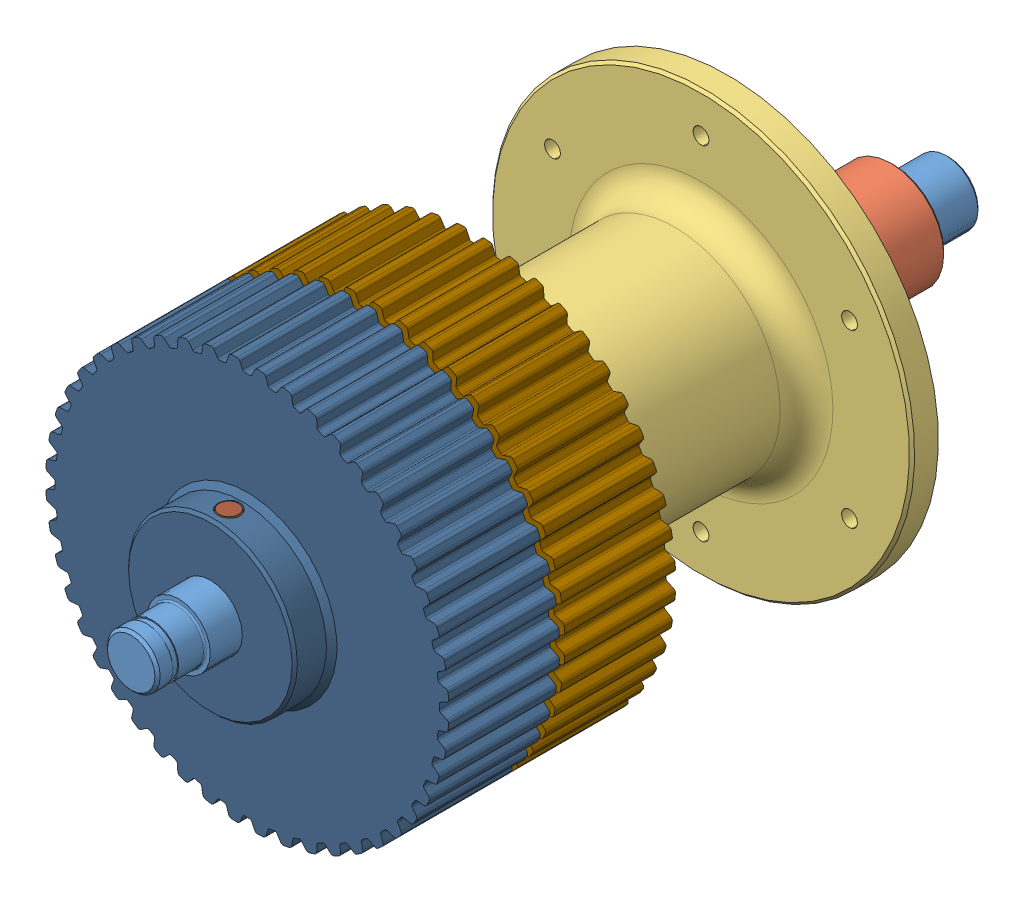
SolidWorks assembly Coaxial Shaft Assembly, configuration Default. Lengths in mm.
Overall size (109.28 109.28 155).
87 component instances, 12 part files, 29 mates.
Components (placement in the parent):
- Inner Shaft-1: Inner Shaft [Default] at (94.2981 61.5422 207.3778) x (0 0 -1) z (1 0 0) size (155 12 12)
- Outer Shaft-1: Outer Shaft [Default] at (94.2981 61.5422 163.3778) x (0 0 -1) z (-1 0 0) size (100.5 20 20)
- Flange-1: Flange [Default] at (94.2981 61.5422 94.3778) x (-0.866025 0.5 0) z (0 0 1) size (80 80 40)
- SKF - 61804 - 18,SI,NC,18_68-5: SKF - 61804 - 18,SI,NC,18_68 [SKF - 61804 - 18,SI,NC,18_68] at (94.2981 61.5422 97.8778) x (0 0 1) z (-0.071685 -0.997427 0) size (7 32 32)
- SKF - 61804 - 18,SI,NC,18_68-6: SKF - 61804 - 18,SI,NC,18_68 [SKF - 61804 - 18,SI,NC,18_68] at (94.2981 61.5422 130.8778) x (0 0 1) z (-1 0 0) size (7 32 32)
- Circlip DIN 471 - 20 x 1.2-3: Circlip DIN 471 - 20 x 1.2 [Circlip DIN 471 - 20 x 1.2] at (94.2981 61.5422 93.0778) x (-1 0 0) z (0 0 -1) size (22.81 25.6 1.2)
- HK_1210-1: HK_1210 [Default] at (94.2981 61.5422 163.3778) x (0 0 -1) z (1 0 0) size (10 16 16)
  - _HK_1210_PART1_2-1: _HK_1210_PART1_2 [Default] at origin size (10 16 16)
  - _HK_1210_PART2_4-1: _HK_1210_PART2_4 [Default] at origin size (6.3 1.5 1.5)
  - _HK_1210_PART2_4-2: _HK_1210_PART2_4 [Default] x (1 0 0) z (0 0.34202 0.939693) size (6.3 1.5 1.5)
  - _HK_1210_PART2_4-3: _HK_1210_PART2_4 [Default] x (1 0 0) z (0 0.642788 0.766044) size (6.3 1.5 1.5)
  - _HK_1210_PART2_4-4: _HK_1210_PART2_4 [Default] x (1 0 0) z (0 0.866025 0.5) size (6.3 1.5 1.5)
  - _HK_1210_PART2_4-5: _HK_1210_PART2_4 [Default] x (1 0 0) z (0 0.984808 0.173648) size (6.3 1.5 1.5)
  - _HK_1210_PART2_4-6: _HK_1210_PART2_4 [Default] x (1 0 0) z (0 0.984808 -0.173648) size (6.3 1.5 1.5)
  - _HK_1210_PART2_4-7: _HK_1210_PART2_4 [Default] x (1 0 0) z (0 0.866025 -0.5) size (6.3 1.5 1.5)
  - _HK_1210_PART2_4-8: _HK_1210_PART2_4 [Default] x (1 0 0) z (0 0.642788 -0.766044) size (6.3 1.5 1.5)
  - _HK_1210_PART2_4-9: _HK_1210_PART2_4 [Default] x (1 0 0) z (0 0.34202 -0.939693) size (6.3 1.5 1.5)
  - _HK_1210_PART2_4-10: _HK_1210_PART2_4 [Default] x (1 0 0) z (0 0 -1) size (6.3 1.5 1.5)
  - _HK_1210_PART2_4-11: _HK_1210_PART2_4 [Default] x (1 0 0) z (0 -0.34202 -0.939693) size (6.3 1.5 1.5)
  - _HK_1210_PART2_4-12: _HK_1210_PART2_4 [Default] x (1 0 0) z (0 -0.642788 -0.766044) size (6.3 1.5 1.5)
  - _HK_1210_PART2_4-13: _HK_1210_PART2_4 [Default] x (1 0 0) z (0 -0.866025 -0.5) size (6.3 1.5 1.5)
  - _HK_1210_PART2_4-14: _HK_1210_PART2_4 [Default] x (1 0 0) z (0 -0.984808 -0.173648) size (6.3 1.5 1.5)
  - _HK_1210_PART2_4-15: _HK_1210_PART2_4 [Default] x (1 0 0) z (0 -0.984808 0.173648) size (6.3 1.5 1.5)
  - _HK_1210_PART2_4-16: _HK_1210_PART2_4 [Default] x (1 0 0) z (0 -0.866025 0.5) size (6.3 1.5 1.5)
  - _HK_1210_PART2_4-17: _HK_1210_PART2_4 [Default] x (1 0 0) z (0 -0.642788 0.766044) size (6.3 1.5 1.5)
  - _HK_1210_PART2_4-18: _HK_1210_PART2_4 [Default] x (1 0 0) z (0 -0.34202 0.939693) size (6.3 1.5 1.5)
  - _HK_1210_PART3_23-1: _HK_1210_PART3_23 [Default] at origin size (6.3 1.5 1.5)
  - _HK_1210_PART3_23-2: _HK_1210_PART3_23 [Default] x (1 0 0) z (0 0.34202 0.939693) size (6.3 1.5 1.5)
  - _HK_1210_PART3_23-3: _HK_1210_PART3_23 [Default] x (1 0 0) z (0 0.642788 0.766044) size (6.3 1.5 1.5)
  - _HK_1210_PART3_23-4: _HK_1210_PART3_23 [Default] x (1 0 0) z (0 0.866025 0.5) size (6.3 1.5 1.5)
  - _HK_1210_PART3_23-5: _HK_1210_PART3_23 [Default] x (1 0 0) z (0 0.984808 0.173648) size (6.3 1.5 1.5)
  - _HK_1210_PART3_23-6: _HK_1210_PART3_23 [Default] x (1 0 0) z (0 0.984808 -0.173648) size (6.3 1.5 1.5)
  - _HK_1210_PART3_23-7: _HK_1210_PART3_23 [Default] x (1 0 0) z (0 0.866025 -0.5) size (6.3 1.5 1.5)
  - _HK_1210_PART3_23-8: _HK_1210_PART3_23 [Default] x (1 0 0) z (0 0.642788 -0.766044) size (6.3 1.5 1.5)
  - _HK_1210_PART3_23-9: _HK_1210_PART3_23 [Default] x (1 0 0) z (0 0.34202 -0.939693) size (6.3 1.5 1.5)
  - _HK_1210_PART3_23-10: _HK_1210_PART3_23 [Default] x (1 0 0) z (0 0 -1) size (6.3 1.5 1.5)
  - _HK_1210_PART3_23-11: _HK_1210_PART3_23 [Default] x (1 0 0) z (0 -0.34202 -0.939693) size (6.3 1.5 1.5)
  - _HK_1210_PART3_23-12: _HK_1210_PART3_23 [Default] x (1 0 0) z (0 -0.642788 -0.766044) size (6.3 1.5 1.5)
  - _HK_1210_PART3_23-13: _HK_1210_PART3_23 [Default] x (1 0 0) z (0 -0.866025 -0.5) size (6.3 1.5 1.5)
  - _HK_1210_PART3_23-14: _HK_1210_PART3_23 [Default] x (1 0 0) z (0 -0.984808 -0.173648) size (6.3 1.5 1.5)
  - _HK_1210_PART3_23-15: _HK_1210_PART3_23 [Default] x (1 0 0) z (0 -0.984808 0.173648) size (6.3 1.5 1.5)
  - _HK_1210_PART3_23-16: _HK_1210_PART3_23 [Default] x (1 0 0) z (0 -0.866025 0.5) size (6.3 1.5 1.5)
  - _HK_1210_PART3_23-17: _HK_1210_PART3_23 [Default] x (1 0 0) z (0 -0.642788 0.766044) size (6.3 1.5 1.5)
  - _HK_1210_PART3_23-18: _HK_1210_PART3_23 [Default] x (1 0 0) z (0 -0.34202 0.939693) size (6.3 1.5 1.5)
- HK_1210-2: HK_1210 [Default] at (94.2981 61.5422 72.8778) x (0 0 -1) z (1 0 0) size (10 16 16)
  - _HK_1210_PART1_2-1: _HK_1210_PART1_2 [Default] at origin size (10 16 16)
  - _HK_1210_PART2_4-1: _HK_1210_PART2_4 [Default] at origin size (6.3 1.5 1.5)
  - _HK_1210_PART2_4-2: _HK_1210_PART2_4 [Default] x (1 0 0) z (0 0.34202 0.939693) size (6.3 1.5 1.5)
  - _HK_1210_PART2_4-3: _HK_1210_PART2_4 [Default] x (1 0 0) z (0 0.642788 0.766044) size (6.3 1.5 1.5)
  - _HK_1210_PART2_4-4: _HK_1210_PART2_4 [Default] x (1 0 0) z (0 0.866025 0.5) size (6.3 1.5 1.5)
  - _HK_1210_PART2_4-5: _HK_1210_PART2_4 [Default] x (1 0 0) z (0 0.984808 0.173648) size (6.3 1.5 1.5)
  - _HK_1210_PART2_4-6: _HK_1210_PART2_4 [Default] x (1 0 0) z (0 0.984808 -0.173648) size (6.3 1.5 1.5)
  - _HK_1210_PART2_4-7: _HK_1210_PART2_4 [Default] x (1 0 0) z (0 0.866025 -0.5) size (6.3 1.5 1.5)
  - _HK_1210_PART2_4-8: _HK_1210_PART2_4 [Default] x (1 0 0) z (0 0.642788 -0.766044) size (6.3 1.5 1.5)
  - _HK_1210_PART2_4-9: _HK_1210_PART2_4 [Default] x (1 0 0) z (0 0.34202 -0.939693) size (6.3 1.5 1.5)
  - _HK_1210_PART2_4-10: _HK_1210_PART2_4 [Default] x (1 0 0) z (0 0 -1) size (6.3 1.5 1.5)
  - _HK_1210_PART2_4-11: _HK_1210_PART2_4 [Default] x (1 0 0) z (0 -0.34202 -0.939693) size (6.3 1.5 1.5)
  - _HK_1210_PART2_4-12: _HK_1210_PART2_4 [Default] x (1 0 0) z (0 -0.642788 -0.766044) size (6.3 1.5 1.5)
  - _HK_1210_PART2_4-13: _HK_1210_PART2_4 [Default] x (1 0 0) z (0 -0.866025 -0.5) size (6.3 1.5 1.5)
  - _HK_1210_PART2_4-14: _HK_1210_PART2_4 [Default] x (1 0 0) z (0 -0.984808 -0.173648) size (6.3 1.5 1.5)
  - _HK_1210_PART2_4-15: _HK_1210_PART2_4 [Default] x (1 0 0) z (0 -0.984808 0.173648) size (6.3 1.5 1.5)
  - _HK_1210_PART2_4-16: _HK_1210_PART2_4 [Default] x (1 0 0) z (0 -0.866025 0.5) size (6.3 1.5 1.5)
  - _HK_1210_PART2_4-17: _HK_1210_PART2_4 [Default] x (1 0 0) z (0 -0.642788 0.766044) size (6.3 1.5 1.5)
  - _HK_1210_PART2_4-18: _HK_1210_PART2_4 [Default] x (1 0 0) z (0 -0.34202 0.939693) size (6.3 1.5 1.5)
  - _HK_1210_PART3_23-1: _HK_1210_PART3_23 [Default] at origin size (6.3 1.5 1.5)
  - _HK_1210_PART3_23-2: _HK_1210_PART3_23 [Default] x (1 0 0) z (0 0.34202 0.939693) size (6.3 1.5 1.5)
  - _HK_1210_PART3_23-3: _HK_1210_PART3_23 [Default] x (1 0 0) z (0 0.642788 0.766044) size (6.3 1.5 1.5)
  - _HK_1210_PART3_23-4: _HK_1210_PART3_23 [Default] x (1 0 0) z (0 0.866025 0.5) size (6.3 1.5 1.5)
  - _HK_1210_PART3_23-5: _HK_1210_PART3_23 [Default] x (1 0 0) z (0 0.984808 0.173648) size (6.3 1.5 1.5)
  - _HK_1210_PART3_23-6: _HK_1210_PART3_23 [Default] x (1 0 0) z (0 0.984808 -0.173648) size (6.3 1.5 1.5)
  - _HK_1210_PART3_23-7: _HK_1210_PART3_23 [Default] x (1 0 0) z (0 0.866025 -0.5) size (6.3 1.5 1.5)
  - _HK_1210_PART3_23-8: _HK_1210_PART3_23 [Default] x (1 0 0) z (0 0.642788 -0.766044) size (6.3 1.5 1.5)
  - _HK_1210_PART3_23-9: _HK_1210_PART3_23 [Default] x (1 0 0) z (0 0.34202 -0.939693) size (6.3 1.5 1.5)
  - _HK_1210_PART3_23-10: _HK_1210_PART3_23 [Default] x (1 0 0) z (0 0 -1) size (6.3 1.5 1.5)
  - _HK_1210_PART3_23-11: _HK_1210_PART3_23 [Default] x (1 0 0) z (0 -0.34202 -0.939693) size (6.3 1.5 1.5)
  - _HK_1210_PART3_23-12: _HK_1210_PART3_23 [Default] x (1 0 0) z (0 -0.642788 -0.766044) size (6.3 1.5 1.5)
  - _HK_1210_PART3_23-13: _HK_1210_PART3_23 [Default] x (1 0 0) z (0 -0.866025 -0.5) size (6.3 1.5 1.5)
  - _HK_1210_PART3_23-14: _HK_1210_PART3_23 [Default] x (1 0 0) z (0 -0.984808 -0.173648) size (6.3 1.5 1.5)
  - _HK_1210_PART3_23-15: _HK_1210_PART3_23 [Default] x (1 0 0) z (0 -0.984808 0.173648) size (6.3 1.5 1.5)
  - _HK_1210_PART3_23-16: _HK_1210_PART3_23 [Default] x (1 0 0) z (0 -0.866025 0.5) size (6.3 1.5 1.5)
  - _HK_1210_PART3_23-17: _HK_1210_PART3_23 [Default] x (1 0 0) z (0 -0.642788 0.766044) size (6.3 1.5 1.5)
  - _HK_1210_PART3_23-18: _HK_1210_PART3_23 [Default] x (1 0 0) z (0 -0.34202 0.939693) size (6.3 1.5 1.5)
- Outer Timing Belt Gear-1: Outer Timing Belt Gear [Default] at (94.2981 61.5422 163.3778) x (1 0 0) z (0 0 -1) size (76.29 76.29 29)
- Inner Timing Belt Gear-1: Inner Timing Belt Gear [Default] at (94.2981 61.5422 164.3778) size (76.29 76.29 28)
- ISO 8734 - 4 x 32 - A - St-3: ISO 8734 - 4 x 32 - A - St [ISO 8734 - 4 x 32 - A - St] at (94.2981 45.5422 188.8778) x (0 1 0) z (0.480016 0 0.87726) size (32 4 4)
- ISO 4762 M3 x 12 - 12C-3: ISO 4762 M3 x 12 - 12C [ISO 4762 M3 x 12 - 12C] at (94.2981 39.5422 138.8778) x (0 1 0) z (0.922632 0 -0.385681) size (15 5.5 5.5)
- ISO 4762 M3 x 12 - 12C-4: ISO 4762 M3 x 12 - 12C [ISO 4762 M3 x 12 - 12C] at (94.2981 83.5422 138.8778) x (0 -1 0) z (0.974179 0 0.225776) size (15 5.5 5.5)
Mates (geometry in assembly coordinates):
- Concentric22: concentric: cylinder of Inner Shaft-1 through (94.2981 61.5422 52.3778) axis (0 0 1) radius 6; cylinder of Outer Shaft-1 through (94.2981 61.5422 62.8778) axis (0 0 1) radius 7
- Concentric23: concentric: cylinder of Outer Shaft-1 through (94.2981 61.5422 62.8778) axis (0 0 1) radius 10; cylinder of Flange-1 through (94.2981 61.5422 150.679) axis (0 0 1) radius 14.5
- Concentric466: concentric: cylinder of Outer Shaft-1 through (94.2981 61.5422 62.8778) axis (0 0 1) radius 10; cylinder of SKF - 61804 - 18,SI,NC,18_68-5 through (94.2981 61.5422 77.2403) axis (0 0 1) radius 10
- Concentric467: concentric: cylinder of Outer Shaft-1 through (94.2981 61.5422 62.8778) axis (0 0 1) radius 10; cylinder of SKF - 61804 - 18,SI,NC,18_68-6 through (94.2981 61.5422 110.2403) axis (0 0 1) radius 10
- Concentric4605: concentric: cylinder of Outer Shaft-1 through (94.2981 61.5422 62.8778) axis (0 0 -1) radius 9.5; cylinder of Circlip DIN 471 - 20 x 1.2-3 through (94.2981 61.5422 94.2778) axis (0 0 -1) radius 9.5
- Coincident3144: coincident: plane of Outer Shaft-1 through (94.2981 52.0422 93.0778) normal (0 0 1); plane of Circlip DIN 471 - 20 x 1.2-3 through (94.2981 61.5422 93.0778) normal (0 0 -1)
- Coincident321: coincident: plane of Flange-1 through (86.2981 47.6858 127.3778) normal (0 0 1); plane of SKF - 61804 - 18,SI,NC,18_68-6 through (94.2981 75.7422 127.3778) normal (0 0 -1)
- Parallel3: parallel: plane of Inner Shaft-1 through (94.2981 61.5422 207.3778) normal (1 0 0); plane of assembly through (0 0 0) normal (1 0 0)
- Parallel4: parallel: plane of Outer Shaft-1 through (94.2981 61.5422 163.3778) normal (-1 0 0); plane of assembly through (0 0 0) normal (1 0 0)
- Parallel6: parallel: plane of Circlip DIN 471 - 20 x 1.2-3 through (94.2981 61.5422 93.0778) normal (-1 0 0); plane of assembly through (0 0 0) normal (1 0 0)
- Coincident3147: coincident: plane of Outer Shaft-1 through (94.2981 51.5422 94.3778) normal (0 0 -1); plane of SKF - 61804 - 18,SI,NC,18_68-5 through (82.5284 62.3881 94.3778) normal (0 0 -1)
- Coincident3148: coincident: plane of Flange-1 through (94.2981 61.5422 94.3778) normal (0 0 -1); plane of SKF - 61804 - 18,SI,NC,18_68-5 through (80.1346 62.5602 94.3778) normal (0 0 -1)
- Concentric4606: concentric: cylinder of Inner Shaft-1 through (94.2981 61.5422 52.3778) axis (0 0 1) radius 6; cylinder of HK_1210-1/_HK_1210_PART1_2-1 through (94.2981 61.5422 113.3778) axis (0 0 1) radius 8
- Coincident3149: coincident: plane of Outer Shaft-1 through (94.2981 61.5422 153.3778) normal (0 0 1); plane of HK_1210-1/_HK_1210_PART1_2-1 through (94.2981 67.9172 153.3778) normal (0 0 -1)
- Parallel7: parallel: plane of ? through (94.2981 61.5422 163.3778) normal (1 0 0); plane of assembly through (0 0 0) normal (1 0 0)
- Concentric4607: concentric: cylinder of Inner Shaft-1 through (94.2981 61.5422 52.3778) axis (0 0 1) radius 6; cylinder of HK_1210-2/_HK_1210_PART1_2-1 through (94.2981 61.5422 22.8778) axis (0 0 1) radius 8
- Coincident3151: coincident: plane of Outer Shaft-1 through (94.2981 61.5422 72.8778) normal (0 0 -1); plane of HK_1210-2/_HK_1210_PART1_2-1 through (94.2981 69.1422 72.8778) normal (0 0 1)
- Parallel8: parallel: plane of ? through (94.2981 61.5422 72.8778) normal (1 0 0); plane of assembly through (0 0 0) normal (1 0 0)
- Concentric4648773: concentric: cylinder of Outer Shaft-1 through (94.2981 61.5422 62.8778) axis (0 0 1) radius 10; cylinder of Outer Timing Belt Gear-1 through (94.2981 61.5422 163.3778) axis (0 0 -1) radius 10.3
- Coincident3175772: coincident: plane of Outer Shaft-1 through (94.2981 61.5422 163.3778) normal (0 0 1); plane of Outer Timing Belt Gear-1 through (94.2981 61.5422 163.3778) normal (0 0 1)
- Concentric4648774: concentric: cylinder of Outer Shaft-1 through (94.2981 71.5422 138.8778) axis (0 -1 0) radius 1.5; cylinder of Outer Timing Belt Gear-1 through (94.2981 81.5422 138.8778) axis (0 -1 0) radius 1.4
- Concentric4648772: concentric: cylinder of Inner Timing Belt Gear-1 through (94.2981 61.5422 164.3778) axis (0 0 1) radius 6.075; cylinder of Inner Shaft-1 through (94.2981 61.5422 52.3778) axis (0 0 1) radius 6
- Parallel2: parallel: cylinder of Inner Timing Belt Gear-1 through (94.2981 36.5422 188.8778) axis (0 1 0) radius 2.075; cylinder of Inner Shaft-1 through (94.2981 51.5422 188.8778) axis (0 1 0) radius 2
- Concentric4648803: concentric: cylinder of Inner Timing Belt Gear-1 through (94.2981 36.5422 188.8778) axis (0 1 0) radius 2.075; cone of ISO 8734 - 4 x 32 - A - St-3 through (94.2981 77.5422 188.8778) axis (0 1 0)
- Tangent6: tangent: cylinder of Inner Timing Belt Gear-1 through (94.2981 61.5422 192.3778) axis (0 0 -1) radius 16; plane of ISO 8734 - 4 x 32 - A - St-3 through (94.2981 77.5422 188.8778) normal (0 1 0)
- Concentric4648804: concentric: cylinder of Outer Timing Belt Gear-1 through (94.2981 81.5422 138.8778) axis (0 -1 0) radius 1.4; cylinder of ISO 4762 M3 x 12 - 12C-3 through (94.2981 7.7922 138.8778) axis (0 -1 0) radius 2.75
- Concentric46488051: concentric: cylinder of Outer Timing Belt Gear-1 through (94.2981 81.5422 138.8778) axis (0 -1 0) radius 1.4; cylinder of ISO 4762 M3 x 12 - 12C-4 through (94.2981 115.2922 138.8778) axis (0 1 0) radius 2.75
- Tangent7: tangent: cylinder of Outer Timing Belt Gear-1 through (94.2981 61.5422 135.3778) axis (0 0 1) radius 19; plane of ISO 4762 M3 x 12 - 12C-4 through (94.919 80.5422 136.1988) normal (0 -1 0)
- Tangent8: tangent: cylinder of Outer Timing Belt Gear-1 through (94.2981 61.5422 135.3778) axis (0 0 1) radius 19; plane of ISO 4762 M3 x 12 - 12C-3 through (95.3587 42.5422 141.415) normal (0 1 0)
